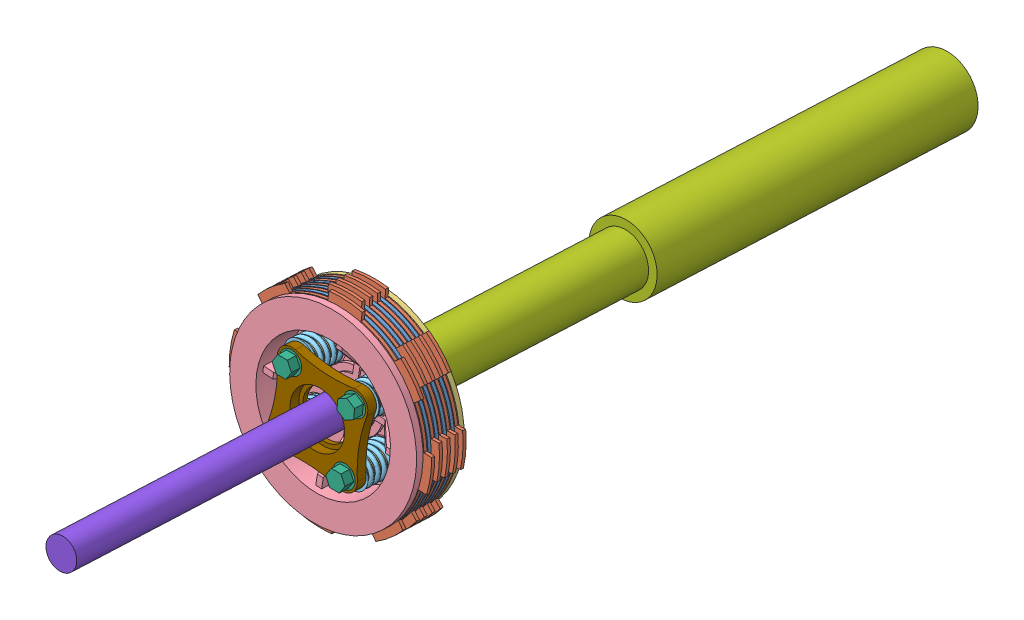
SolidWorks assembly Assem1, configuration Default. Lengths in mm.
Overall size (143.29 143.18 551.52).
22 component instances, 9 part files, 32 mates.
Components (placement in the parent):
- Part2-1: Part2 [Default] at (-41.147 22.9312 483.0557) x (-0.99949 0.017202 0.026901) z (-0.028075 -0.072099 -0.997002) size (109.84 109.84 1.95)
- Part3-1: Part3 [Default] at (-41.0788 23.1064 485.4785) x (-0.996166 0.084687 0.021928) z (-0.028075 -0.072099 -0.997002) size (118.65 118.65 2.96)
- Part4-1: Part4 [Default] at (-41.7827 21.2988 460.4836) x (-0.092039 -0.992972 0.0744) z (0.028075 0.072099 0.997002) size (109.7 109.7 29.84)
- Part5-1: Part5 [Default] at (-41.0639 23.1446 486.0069) x (0.99536 -0.093852 -0.021242) z (-0.028075 -0.072099 -0.997002) size (109.56 109.56 38.35)
- part6-1: part6 [Default] at (-23.6138 3.2321 497.2107) x (-0.443882 0.894564 -0.052192) z (-0.895645 -0.441086 0.057119) size (18.84 22.89 18.68)
- Part7-1: Part7 [Default] at (-23.6864 3.0457 494.634) x (-0.922975 -0.381116 0.053552) z (-0.383834 0.921712 -0.055846) size (13 30.3 13)
- Part8-1: Part8 [Default] at (-41.9862 20.7761 453.2554) x (-0.922975 -0.381116 0.053552) z (-0.028075 -0.072099 -0.997002) size (40 40 350)
- Part9-1: Part9 [Default] at (-36.3711 35.196 652.6558) x (-0.922975 -0.381116 0.053552) z (-0.028075 -0.072099 -0.997002) size (18 18 200)
- Part2-2: Part2 [Default] at (-41.2849 22.5771 478.1605) x (-0.924938 0.380116 -0.001443) z (-0.028075 -0.072099 -0.997002) size (109.84 109.84 1.95)
- Part2-3: Part2 [Default] at (-41.4227 22.2231 473.2652) x (0.98175 0.185689 -0.041074) z (-0.028075 -0.072099 -0.997002) size (109.84 109.84 1.95)
- Part2-4: Part2 [Default] at (-41.5606 21.8691 468.3699) x (-0.983272 0.181558 0.014559) z (-0.028075 -0.072099 -0.997002) size (109.84 109.84 1.95)
- Part3-2: Part3 [Default] at (-41.2167 22.7523 480.5832) x (-0.999605 0.001014 0.028075) z (-0.028075 -0.072099 -0.997002) size (118.65 118.65 2.96)
- Part3-6: Part3 [Default] at (-41.4924 22.0443 470.7926) x (-0.999605 0.001014 0.028075) z (-0.028075 -0.072099 -0.997002) size (118.65 118.65 2.96)
- Part3-7: Part3 [Default] at (-41.6302 21.6903 465.8973) x (-0.999605 0.000786 0.028092) z (-0.028075 -0.072099 -0.997002) size (118.65 118.65 2.96)
- Part3-8: Part3 [Default] at (-41.3545 22.3983 475.6879) x (-0.999605 0.001014 0.028075) z (-0.028075 -0.072099 -0.997002) size (118.65 118.65 2.96)
- part6-5: part6 [Default] at (-20.1163 40.965 494.3835) x (-0.895645 -0.441086 0.057119) z (0.443882 -0.894564 0.052192) size (18.84 22.89 18.68)
- part6-6: part6 [Default] at (-57.94 44.5314 495.1907) x (0.443882 -0.894564 0.052192) z (0.895645 0.441086 -0.057119) size (18.84 22.89 18.68)
- part6-7: part6 [Default] at (-61.4375 6.7985 498.0179) x (0.895645 0.441086 -0.057119) z (-0.443882 0.894564 -0.052192) size (18.84 22.89 18.68)
- Part1-2: Part1 [Default] at (-40.8494 23.6954 493.624) x (0.092038 0.992972 -0.0744) z (-0.028075 -0.072099 -0.997002) size (53.6 53.62 8.1)
- Part7-5: Part7 [Default] at (-61.51 6.6121 495.4412) x (-0.383834 0.921712 -0.055846) z (0.922975 0.381116 -0.053552) size (13 30.3 13)
- Part7-6: Part7 [Default] at (-58.0125 44.3451 492.614) x (0.922975 0.381116 -0.053552) z (0.383834 -0.921712 0.055846) size (13 30.3 13)
- Part7-7: Part7 [Default] at (-20.1889 40.7787 491.8068) x (0.383834 -0.921712 0.055846) z (-0.922975 -0.381116 0.053552) size (13 30.3 13)
Mates (geometry in assembly coordinates):
- Concentric12: concentric aligned: circle of Part3-1; circle of Part5-1
- Coincident10: coincident anti-aligned: plane of Part3-1 through (-41.0639 23.1446 486.0069) normal (0.028075 0.072099 0.997002); plane of Part5-1 through (-41.0639 23.1446 486.0069) normal (-0.028075 -0.072099 -0.997002)
- Concentric13: concentric aligned: circle of Part2-1; circle of Part5-1
- Concentric15: concentric anti-aligned: cylinder of Part2-1 through (-41.147 22.9312 483.0557) axis (-0.028075 -0.072099 -0.997002) radius 45.085; cylinder of Part5-1 through (-41.7321 21.4286 462.2782) axis (0.028075 0.072099 0.997002) radius 44.705
- Coincident11: coincident anti-aligned: plane of Part2-1 through (-41.147 22.9312 483.0557) normal (0.028075 0.072099 0.997002); plane of Part3-1 through (-41.147 22.9312 483.0557) normal (-0.028075 -0.072099 -0.997002)
- Concentric16: concentric aligned: circle of Part5-1; circle of Part3-2
- Coincident12: coincident anti-aligned: plane of Part2-1 through (-41.2018 22.7906 481.1116) normal (-0.028075 -0.072099 -0.997002); plane of Part3-2 through (-41.2018 22.7906 481.1116) normal (0.028075 0.072099 0.997002)
- Concentric17: concentric aligned: circle of Part5-1; circle of Part2-2
- Coincident13: coincident anti-aligned: plane of Part2-2 through (-41.2849 22.5771 478.1605) normal (0.028075 0.072099 0.997002); plane of Part3-2 through (-41.2849 22.5771 478.1605) normal (-0.028075 -0.072099 -0.997002)
- Concentric19: concentric aligned: circle of Part5-1; circle of Part3-8
- Coincident16: coincident anti-aligned: plane of Part2-2 through (-41.3396 22.4366 476.2163) normal (-0.028075 -0.072099 -0.997002); plane of Part3-8 through (-41.3396 22.4366 476.2163) normal (0.028075 0.072099 0.997002)
- Concentric20: concentric aligned: circle of Part5-1; circle of Part2-3
- Coincident17: coincident anti-aligned: plane of Part2-3 through (-41.4227 22.2231 473.2652) normal (0.028075 0.072099 0.997002); plane of Part3-8 through (-41.4227 22.2231 473.2652) normal (-0.028075 -0.072099 -0.997002)
- Concentric21: concentric aligned: circle of Part5-1; circle of Part3-6
- Coincident18: coincident anti-aligned: plane of Part2-3 through (-41.4775 22.0825 471.321) normal (-0.028075 -0.072099 -0.997002); plane of Part3-6 through (-41.4775 22.0825 471.321) normal (0.028075 0.072099 0.997002)
- Concentric22: concentric aligned: circle of Part5-1; circle of Part2-4
- Coincident19: coincident anti-aligned: plane of Part2-4 through (-41.5606 21.8691 468.3699) normal (0.028075 0.072099 0.997002); plane of Part3-6 through (-41.5606 21.8691 468.3699) normal (-0.028075 -0.072099 -0.997002)
- Concentric23: concentric aligned: circle of Part5-1; circle of Part3-7
- Coincident20: coincident anti-aligned: plane of Part2-4 through (-41.6153 21.7285 466.4258) normal (-0.028075 -0.072099 -0.997002); plane of Part3-7 through (-41.6153 21.7285 466.4258) normal (0.028075 0.072099 0.997002)
- Concentric24: concentric aligned: circle of Part4-1; circle of Part5-1
- Concentric25: concentric anti-aligned: circle of Part4-1; circle of Part5-1
- Coincident22: coincident anti-aligned: plane of Part4-1 through (-41.6984 21.5151 463.4746) normal (0.028075 0.072099 0.997002); plane of Part3-7 through (-41.6984 21.5151 463.4746) normal (-0.028075 -0.072099 -0.997002)
- Concentric26: concentric: cone of Part4-1 through (-24.6196 0.6492 461.4936) axis (0.028075 0.072099 0.997002); point of part6-1
- Coincident28: coincident anti-aligned: plane of Part5-1 through (-24.4006 1.2115 469.2702) normal (0.028075 0.072099 0.997002); plane of part6-1 through (-35.8934 -22.7949 471.3299) normal (-0.028075 -0.072099 -0.997002)
- Concentric36: concentric aligned: circle of Part5-1; circle of Part1-2
- Concentric37: concentric aligned: circle of Part4-1; circle of Part1-2
- Coincident32: coincident anti-aligned: plane of part6-1 through (-51.2584 9.6212 489.4785) normal (0.028075 0.072099 0.997002); plane of Part1-2 through (-41.0022 23.3032 488.2003) normal (-0.028075 -0.072099 -0.997002)
- Concentric38: concentric aligned: circle of Part7-1; circle of Part1-2
- Coincident34: coincident aligned: circle of Part7-1; circle of Part1-2
- Concentric41: concentric anti-aligned: circle of Part5-1; circle of Part8-1
- Coincident39: coincident anti-aligned: plane of Part5-1 through (-41.9862 20.7761 453.2554) normal (-0.028075 -0.072099 -0.997002); plane of Part8-1 through (-41.9862 20.7761 453.2554) normal (0.028075 0.072099 0.997002)
- Coincident40: coincident anti-aligned: circle of Part5-1; circle of Part9-1
